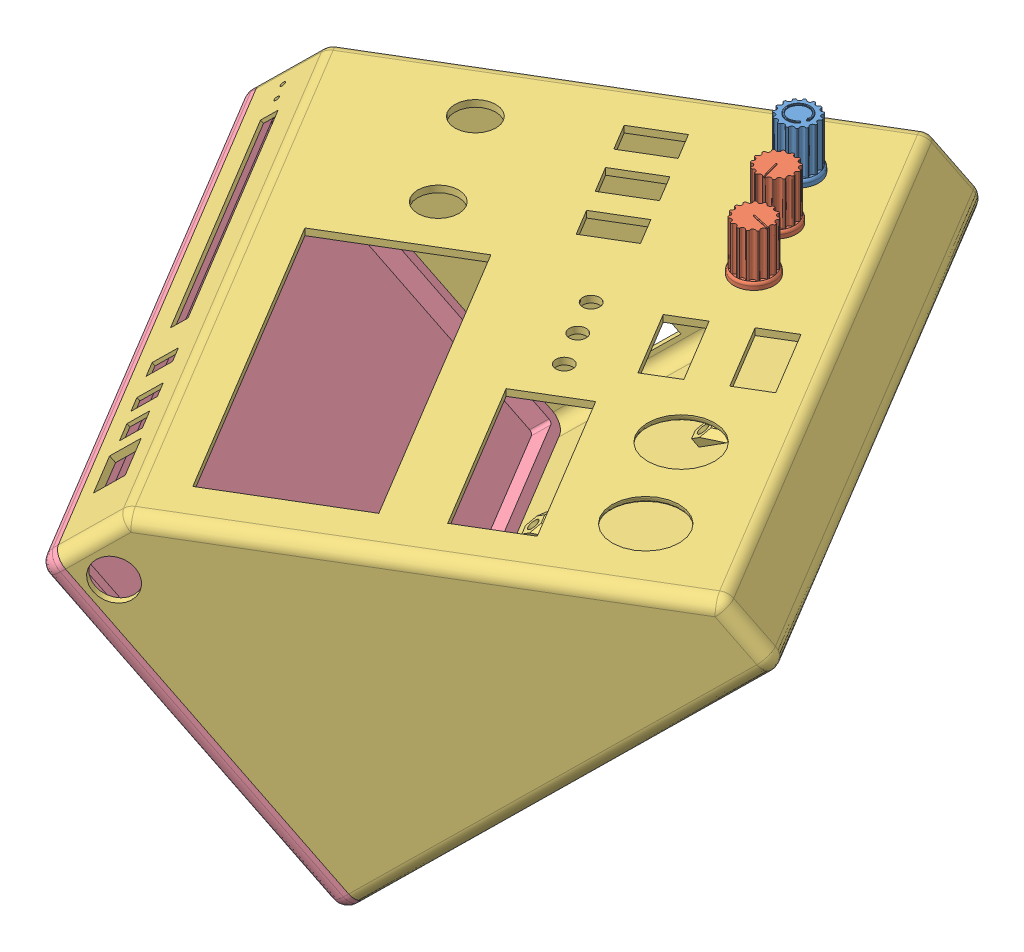
SolidWorks assembly Assembly, configuration Default. Lengths in mm.
Overall size (232.58 160.27 238.33).
5 component instances, 4 part files, 7 mates.
Components (placement in the parent):
- Encoder Dial-1: Encoder Dial [Default] at (-38.4695 -7.2204 40.203) size (12 15.31 12)
- Pot Dial-1: Pot Dial [Default] at (-28.5898 -7.2204 56.6806) x (0.349348 0 -0.936993) z (0.936993 0 0.349348) size (12 15.3 12)
- SwitchBox-1: SwitchBox [Default] at (-12.8147 -61.1086 102.6934) x (-0.514235 0 -0.857649) z (0.656998 0.642788 -0.393927) size (180 104.41 120)
- SwitchCover-1: SwitchCover [Default] at (-12.4862 -60.7872 102.4965) x (-0.514235 0 -0.857649) z (0.656998 0.642788 -0.393927) size (180 103.91 7.5)
- Pot Dial-2: Pot Dial [Default] at (-18.6009 -7.2204 73.3402) x (-0.670916 0 -0.741533) z (0.741533 0 -0.670916) size (12 15.3 12)
Mates (geometry in assembly coordinates):
- Parallel2: parallel aligned: plane of SwitchBox-1 through (-231.0977 -20.0762 -42.0957) normal (-0.551286 0.766044 0.330544); plane of SwitchCover-1 through (-230.7692 -19.7548 -42.2927) normal (-0.551286 0.766044 0.330544)
- Parallel4: parallel aligned: plane of SwitchBox-1 through (61.8606 -7.2204 162.8571) normal (0.514235 0 0.857649); plane of SwitchCover-1 through (62.1891 -6.899 162.6602) normal (0.514235 0 0.857649)
- Coincident5: coincident anti-aligned: line of SwitchBox-1 through (-153.7429 -20.0762 86.918) axis (0.514235 0 0.857649); line of SwitchCover-1 through (-65.2945 -20.0762 234.4337) axis (-0.514235 0 -0.857649)
- Coincident6: coincident aligned: line of SwitchBox-1 through (-61.0324 -23.1404 236.5421) axis (0.551286 -0.766044 -0.330544); line of SwitchCover-1 through (-61.0324 -23.1404 236.5421) axis (0.551286 -0.766044 -0.330544)
- Coincident10: coincident anti-aligned: circle of Encoder Dial-1; circle of SwitchBox-1
- Coincident11: coincident anti-aligned: circle of Pot Dial-1; circle of SwitchBox-1
- Coincident12: coincident anti-aligned: circle of SwitchBox-1; circle of Pot Dial-2
